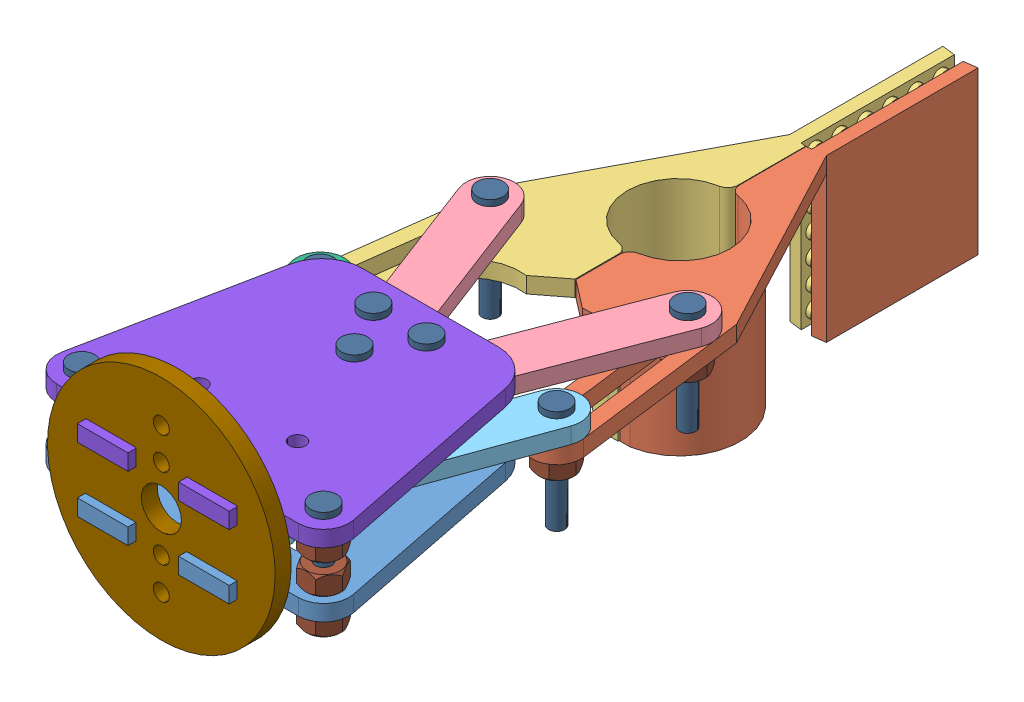
SolidWorks assembly Arm, configuration Default. Lengths in mm.
Overall size (71.68 56.15 161.12).
40 component instances, 11 part files, 49 mates.
Components (placement in the parent):
- Gripper-1: Gripper [Predeterminado] at origin size (71.68 56.15 161.12) (flexible)
  - Base grip-1: Base grip [Predeterminado] at (-28.7905 -8.0804 25) size (57.8 3.17 54.76)
  - Gripp4-3: Gripp4 [Predeterminado] at (12.4224 -1.7304 -60.3347) x (-0.991785 0 0.127916) z (0.127916 0 0.991785) size (24.38 32 109.52)
  - Gripp3-3: Gripp3 [Predeterminado] at (-10.0052 -4.9054 -60.334) x (0.991785 0 0.127918) z (-0.127918 0 0.991785) size (24.38 32 109.76)
  - eslabon dos-1: eslabon dos [Predeterminado] at (9.1489 -1.7304 -39.3826) x (0.356912 0 -0.934138) z (0.934138 0 0.356912) size (49.52 3.17 9.53)
  - eslabon dos-2: eslabon dos [Predeterminado] at (-6.7309 -1.7304 -39.3824) x (0.356954 0 0.934122) z (-0.934122 0 0.356954) size (49.52 3.17 9.53)
  - eslabon engrane servo-1: eslabon engrane servo [Predeterminado] at (22.2446 -1.7304 -6.1851) x (-0.340349 0 0.940299) z (-0.940299 0 -0.340349) size (56.02 3.17 23.48)
  - eslabon engrane servo - copia-1: eslabon engrane servo - copia [Predeterminado] at (-10.8703 -1.7304 -9.4268) x (0.340393 0 0.940283) z (-0.940283 0 0.340393) size (56.51 3.17 22.67)
  - separadores-1: separadores [Predeterminado] at (-8.5405 -4.9054 11) x (0.999665 0 -0.025874) z (0.025874 0 0.999665) size (6.35 3.17 6.35)
  - separadores-2: separadores [Predeterminado] at (-8.5405 1.4446 11) x (0.999761 0 0.021872) z (-0.021872 0 0.999761) size (6.35 3.17 6.35)
  - separadores-4: separadores [Predeterminado] at (-4.0405 -4.9054 -19) x (0.999761 0 0.021872) z (-0.021872 0 0.999761) size (6.35 3.17 6.35)
  - separadores-5: separadores [Predeterminado] at (6.4595 1.4446 -19) x (0.999761 0 0.021872) z (-0.021872 0 0.999761) size (6.35 3.17 6.35)
  - separadores-6: separadores [Predeterminado] at (-4.0405 1.4446 -19) x (0.999761 0 0.021872) z (-0.021872 0 0.999761) size (6.35 3.17 6.35)
  - separadores-7: separadores [Predeterminado] at (6.4595 -4.9054 -19) x (0.999761 0 0.021872) z (-0.021872 0 0.999761) size (6.35 3.17 6.35)
  - bse grip superior-2: bse grip superior [Predeterminado] at (-28.7905 4.6196 25) size (57.8 3.17 54.76)
  - base gripper servo-1: base gripper servo [Predeterminado] at (1.2095 -0.0804 28.175) x (1 0 0) z (0 1 0) size (45 3.17 45)
- Mosmar-1: Mosmar [Default] at (25.1104 8.9946 20) x (0.920505 0 -0.390731) z (0 -1 0) size (5.17 5.17 21.2)
- Mosmar-2: Mosmar [Default] at (-22.1562 2.6446 -26.6113) x (1 0 0) z (0 -1 0) size (5.17 5.17 21.2)
- Mosmar-3: Mosmar [Default] at (24.5734 2.6446 -26.612) x (1 0 0) z (0 -1 0) size (5.17 5.17 21.2)
- Mosmar-4: Mosmar [Default] at (-18.3187 2.6446 -56.3649) x (1 0 0) z (0 -1 0) size (5.17 5.17 21.2)
- Mosmar-5: Mosmar [Default] at (-22.6915 8.9946 20) x (1 0 0) z (0 -1 0) size (5.17 5.17 21.2)
- Mosmar-6: Mosmar [Default] at (20.7359 2.6446 -56.3655) x (1 0 0) z (0 -1 0) size (5.17 5.17 21.2)
- Mosmar-7: Mosmar [Default] at (6.4595 8.9946 -19) x (1 0 0) z (0 -1 0) size (5.17 5.17 21.2)
- Mosmar-8: Mosmar [Default] at (1.2095 8.9946 -10) x (1 0 0) z (0 -1 0) size (5.17 5.17 21.2)
- Mosmar-9: Mosmar [Default] at (-4.0405 8.9946 -19) x (1 0 0) z (0 -1 0) size (5.17 5.17 21.2)
- Nut-1: Nut [Default] at (25.1104 0.8696 20) x (1 0 0) z (0 1 0) size (8.54 7.6 3.75)
- Nut-2: Nut [Default] at (25.1104 -11.8304 20) x (1 0 0) z (0 1 0) size (8.54 7.6 3.75)
- Nut-3: Nut [Default] at (24.5734 -8.6554 -26.612) x (1 0 0) z (0 1 0) size (8.54 7.6 3.75)
- Nut-4: Nut [Default] at (-18.3187 -8.6554 -56.3649) x (1 0 0) z (0 1 0) size (8.54 7.6 3.75)
- Nut-5: Nut [Default] at (25.1104 -4.9054 20) x (1 0 0) z (0 1 0) size (8.54 7.6 3.75)
- Nut-6: Nut [Default] at (-22.6915 0.8696 20) x (1 0 0) z (0 1 0) size (8.54 7.6 3.75)
- Nut-7: Nut [Default] at (-22.6915 -11.8304 20) x (1 0 0) z (0 1 0) size (8.54 7.6 3.75)
- Nut-8: Nut [Default] at (-22.6915 -4.9054 20) x (1 0 0) z (0 1 0) size (8.54 7.6 3.75)
- Nut-9: Nut [Default] at (-22.1562 -8.6554 -26.6113) x (1 0 0) z (0 1 0) size (8.54 7.6 3.75)
- Nut-10: Nut [Default] at (20.7359 -8.6554 -56.3655) x (1 0 0) z (0 1 0) size (8.54 7.6 3.75)
- Nut-11: Nut [Default] at (1.2095 0.8696 -10) x (1 0 0) z (0 1 0) size (8.54 7.6 3.75)
- Nut-12: Nut [Default] at (1.2095 -4.9054 -10) x (1 0 0) z (0 1 0) size (8.54 7.6 3.75)
- Nut-13: Nut [Default] at (1.2095 -11.8304 -10) x (1 0 0) z (0 1 0) size (8.54 7.6 3.75)
- Nut-14: Nut [Default] at (6.4595 -11.8304 -19) x (1 0 0) z (0 1 0) size (8.54 7.6 3.75)
- Nut-15: Nut [Default] at (-4.0405 -11.8304 -19) x (1 0 0) z (0 1 0) size (8.54 7.6 3.75)
Mates (geometry in assembly coordinates):
- Concentric1: concentric anti-aligned: cylinder of Gripper-1/eslabon dos-1 through (20.7359 1.4446 -56.3655) axis (0 -1 0) radius 1.5875; cylinder of Mosmar-6 through (20.7359 -18.5554 -56.3655) axis (0 1 0) radius 1.59
- Coincident1: coincident anti-aligned: plane of Gripper-1/eslabon dos-1 through (6.4595 1.4446 -19) normal (0 1 0); plane of Mosmar-6 through (20.7359 1.4446 -56.3655) normal (0 -1 0)
- Concentric2: concentric anti-aligned: cylinder of Gripper-1/eslabon engrane servo-1 through (24.5734 1.4446 -26.612) axis (0 -1 0) radius 1.5875; cylinder of Mosmar-3 through (24.5734 -18.5554 -26.612) axis (0 1 0) radius 1.59
- Coincident2: coincident anti-aligned: plane of Gripper-1/eslabon engrane servo-1 through (24.5734 1.4446 -26.612) normal (0 1 0); circle of Mosmar-3
- Concentric3: concentric anti-aligned: cylinder of Gripper-1/eslabon dos-2 through (-18.3187 1.4446 -56.3649) axis (0 -1 0) radius 1.5875; cylinder of Mosmar-4 through (-18.3187 -18.5554 -56.3649) axis (0 1 0) radius 1.59
- Coincident3: coincident anti-aligned: plane of Gripper-1/eslabon dos-2 through (-18.3187 1.4446 -56.3649) normal (0 1 0); plane of Mosmar-4 through (-18.3187 1.4446 -56.3649) normal (0 -1 0)
- Concentric4: concentric anti-aligned: cylinder of Gripper-1/eslabon engrane servo - copia-1 through (-22.1562 1.4446 -26.6113) axis (0 -1 0) radius 1.5875; cylinder of Mosmar-2 through (-22.1562 -18.5554 -26.6113) axis (0 1 0) radius 1.59
- Coincident4: coincident anti-aligned: plane of Gripper-1/eslabon engrane servo - copia-1 through (-22.1562 1.4446 -26.6113) normal (0 1 0); plane of Mosmar-2 through (-22.1562 1.4446 -26.6113) normal (0 -1 0)
- Concentric7: concentric aligned: cylinder of Gripper-1/bse grip superior-2 through (25.1104 4.6196 20) axis (0 1 0) radius 1.5875; cylinder of Mosmar-1 through (25.1104 -12.2054 20) axis (0 1 0) radius 1.59
- Coincident5: coincident anti-aligned: plane of Gripper-1/bse grip superior-2 through (14.651 7.7946 -17) normal (0 1 0); plane of Mosmar-1 through (25.1104 7.7946 20) normal (0 -1 0)
- Concentric10: concentric aligned: circle of Gripper-1/bse grip superior-2; cylinder of Mosmar-5 through (-22.6915 -12.2054 20) axis (0 1 0) radius 1.59
- Coincident6: coincident anti-aligned: plane of Gripper-1/bse grip superior-2 through (14.651 7.7946 -17) normal (0 1 0); plane of Mosmar-5 through (-22.6915 7.7946 20) normal (0 -1 0)
- Concentric12: concentric aligned: circle of Gripper-1/bse grip superior-2; cylinder of Mosmar-7 through (6.4595 -12.2054 -19) axis (0 1 0) radius 1.59
- Coincident7: coincident anti-aligned: plane of Gripper-1/bse grip superior-2 through (14.651 7.7946 -17) normal (0 1 0); plane of Mosmar-7 through (6.4595 7.7946 -19) normal (0 -1 0)
- Concentric13: concentric aligned: cylinder of Gripper-1/bse grip superior-2 through (1.2095 4.6196 -10) axis (0 1 0) radius 1.5875; cylinder of Mosmar-8 through (1.2095 -12.2054 -10) axis (0 1 0) radius 1.59
- Coincident8: coincident anti-aligned: plane of Gripper-1/bse grip superior-2 through (14.651 7.7946 -17) normal (0 1 0); plane of Mosmar-8 through (1.2095 7.7946 -10) normal (0 -1 0)
- Concentric14: concentric anti-aligned: cylinder of Gripper-1/bse grip superior-2 through (-4.0405 7.7946 -19) axis (0 -1 0) radius 1.5875; cylinder of Mosmar-9 through (-4.0405 -12.2054 -19) axis (0 1 0) radius 1.59
- Coincident9: coincident anti-aligned: plane of Gripper-1/bse grip superior-2 through (14.651 7.7946 -17) normal (0 1 0); plane of Mosmar-7 through (6.4595 7.7946 -19) normal (0 -1 0)
- Coincident10: coincident anti-aligned: plane of Gripper-1/bse grip superior-2 through (14.651 7.7946 -17) normal (0 1 0); plane of Mosmar-9 through (-4.0405 7.7946 -19) normal (0 -1 0)
- Concentric15: concentric anti-aligned: cylinder of Mosmar-1 through (25.1104 -12.2054 20) axis (0 1 0) radius 1.59; cylinder of Nut-1 through (25.1104 4.6196 20) axis (0 -1 0) radius 1.59
- Coincident11: coincident anti-aligned: plane of Gripper-1/bse grip superior-2 through (14.651 4.6196 -17) normal (0 -1 0); plane of Nut-1 through (25.1104 4.6196 20) normal (0 1 0)
- Concentric16: concentric anti-aligned: cylinder of Mosmar-1 through (25.1104 -12.2054 20) axis (0 1 0) radius 1.59; cylinder of Nut-5 through (25.1104 -1.1554 20) axis (0 -1 0) radius 1.59
- Coincident12: coincident anti-aligned: plane of Gripper-1/Base grip-1 through (14.651 -4.9054 -17) normal (0 1 0); plane of Nut-5 through (25.1104 -4.9054 20) normal (0 -1 0)
- Concentric17: concentric anti-aligned: cylinder of Mosmar-1 through (25.1104 -12.2054 20) axis (0 1 0) radius 1.59; cylinder of Nut-2 through (25.1104 -8.0804 20) axis (0 -1 0) radius 1.59
- Coincident13: coincident anti-aligned: plane of Gripper-1/Base grip-1 through (14.651 -8.0804 -17) normal (0 -1 0); plane of Nut-2 through (25.1104 -8.0804 20) normal (0 1 0)
- Concentric18: concentric anti-aligned: cylinder of Mosmar-5 through (-22.6915 -12.2054 20) axis (0 1 0) radius 1.59; cylinder of Nut-6 through (-22.6915 4.6196 20) axis (0 -1 0) radius 1.59
- Concentric19: concentric anti-aligned: cylinder of Mosmar-5 through (-22.6915 -12.2054 20) axis (0 1 0) radius 1.59; cylinder of Nut-8 through (-22.6915 -1.1554 20) axis (0 -1 0) radius 1.59
- Concentric20: concentric anti-aligned: cylinder of Mosmar-5 through (-22.6915 -12.2054 20) axis (0 1 0) radius 1.59; cylinder of Nut-7 through (-22.6915 -8.0804 20) axis (0 -1 0) radius 1.59
- Coincident14: coincident anti-aligned: plane of Gripper-1/Base grip-1 through (14.651 -8.0804 -17) normal (0 -1 0); plane of Nut-7 through (-22.6915 -8.0804 20) normal (0 1 0)
- Coincident15: coincident anti-aligned: plane of Gripper-1/bse grip superior-2 through (14.651 4.6196 -17) normal (0 -1 0); plane of Nut-6 through (-22.6915 4.6196 20) normal (0 1 0)
- Coincident16: coincident anti-aligned: plane of Gripper-1/Base grip-1 through (14.651 -4.9054 -17) normal (0 1 0); plane of Nut-8 through (-22.6915 -4.9054 20) normal (0 -1 0)
- Concentric21: concentric anti-aligned: cylinder of Mosmar-3 through (24.5734 -18.5554 -26.612) axis (0 1 0) radius 1.59; cylinder of Nut-3 through (24.5734 -4.9054 -26.612) axis (0 -1 0) radius 1.59
- Concentric22: concentric anti-aligned: cylinder of Mosmar-6 through (20.7359 -18.5554 -56.3655) axis (0 1 0) radius 1.59; cylinder of Nut-10 through (20.7359 -4.9054 -56.3655) axis (0 -1 0) radius 1.59
- Concentric23: concentric anti-aligned: cylinder of Mosmar-2 through (-22.1562 -18.5554 -26.6113) axis (0 1 0) radius 1.59; cylinder of Nut-9 through (-22.1562 -4.9054 -26.6113) axis (0 -1 0) radius 1.59
- Concentric25: concentric anti-aligned: cylinder of Mosmar-4 through (-18.3187 -18.5554 -56.3649) axis (0 1 0) radius 1.59; cylinder of Nut-4 through (-18.3187 -4.9054 -56.3649) axis (0 -1 0) radius 1.59
- Coincident17: coincident anti-aligned: plane of Gripper-1/Gripp4-3 through (8.0134 -4.9054 -39.6004) normal (0 -1 0); plane of Nut-3 through (24.5734 -4.9054 -26.612) normal (0 1 0)
- Coincident18: coincident anti-aligned: plane of Gripper-1/Gripp4-3 through (8.0134 -4.9054 -39.6004) normal (0 -1 0); circle of Nut-10
- Coincident19: coincident anti-aligned: plane of Gripper-1/Gripp3-3 through (-5.5962 -4.9054 -39.5997) normal (0 -1 0); plane of Nut-9 through (-22.1562 -4.9054 -26.6113) normal (0 1 0)
- Coincident20: coincident anti-aligned: plane of Gripper-1/Gripp3-3 through (-5.5962 -4.9054 -39.5997) normal (0 -1 0); plane of Nut-4 through (-18.3187 -4.9054 -56.3649) normal (0 1 0)
- Concentric26: concentric anti-aligned: cylinder of Mosmar-8 through (1.2095 -12.2054 -10) axis (0 1 0) radius 1.59; cylinder of Nut-11 through (1.2095 4.6196 -10) axis (0 -1 0) radius 1.59
- Coincident21: coincident anti-aligned: plane of Gripper-1/bse grip superior-2 through (14.651 4.6196 -17) normal (0 -1 0); plane of Nut-11 through (1.2095 4.6196 -10) normal (0 1 0)
- Concentric27: concentric anti-aligned: cylinder of Mosmar-8 through (1.2095 -12.2054 -10) axis (0 1 0) radius 1.59; cylinder of Nut-12 through (1.2095 -1.1554 -10) axis (0 -1 0) radius 1.59
- Coincident22: coincident anti-aligned: plane of Gripper-1/Base grip-1 through (14.651 -4.9054 -17) normal (0 1 0); plane of Nut-12 through (1.2095 -4.9054 -10) normal (0 -1 0)
- Concentric28: concentric anti-aligned: cylinder of Mosmar-8 through (1.2095 -12.2054 -10) axis (0 1 0) radius 1.59; cylinder of Nut-13 through (1.2095 -8.0804 -10) axis (0 -1 0) radius 1.59
- Coincident23: coincident anti-aligned: plane of Gripper-1/Base grip-1 through (14.651 -8.0804 -17) normal (0 -1 0); circle of Nut-13
- Concentric29: concentric anti-aligned: cylinder of Mosmar-7 through (6.4595 -12.2054 -19) axis (0 1 0) radius 1.59; cylinder of Nut-14 through (6.4595 -8.0804 -19) axis (0 -1 0) radius 1.59
- Coincident24: coincident anti-aligned: plane of Gripper-1/Base grip-1 through (14.651 -8.0804 -17) normal (0 -1 0); circle of Nut-14
- Concentric30: concentric anti-aligned: cylinder of Mosmar-9 through (-4.0405 -12.2054 -19) axis (0 1 0) radius 1.59; cylinder of Nut-15 through (-4.0405 -8.0804 -19) axis (0 -1 0) radius 1.59
- Coincident26: coincident anti-aligned: plane of Gripper-1/Base grip-1 through (14.651 -8.0804 -17) normal (0 -1 0); plane of Nut-15 through (-4.0405 -8.0804 -19) normal (0 1 0)
